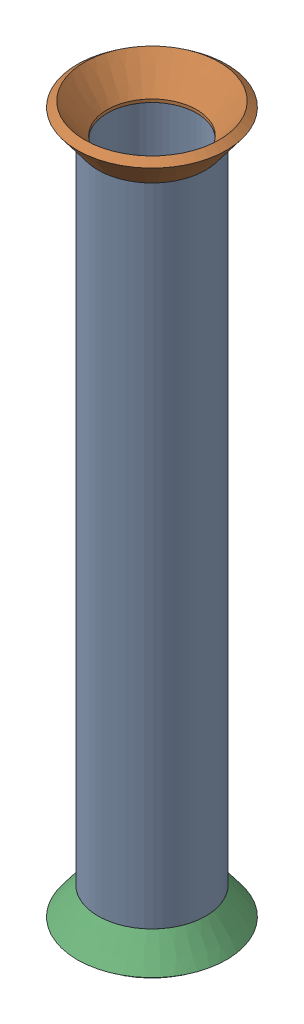
SolidWorks assembly Pipe 9, configuration Default. Lengths in mm.
Overall size (17.61 83.98 17.61).
3 component instances, 2 part files, 4 mates.
Components (placement in the parent):
- Part13-1: Part13 [Default<As Machined>] at origin size (12.7 76.2 12.7)
- Flared pipe end - .5 inch-1: Flared pipe end - .5 inch [Default<As Machined>] at (0 -198.1503 277.2944) x (0.999999 0 -0.001217) z (0 1 0) size (17.59 17.59 3.89)
- Flared pipe end - .5 inch-2: Flared pipe end - .5 inch [Default<As Machined>] at (0 -274.3503 277.2944) x (-1 0 0) z (0 -1 0) size (17.59 17.59 3.89)
Mates (geometry in assembly coordinates):
- Coincident1054: coincident: plane of Part13-1 through (0 -198.1503 277.2944) normal (0 1 0); plane of Flared pipe end - .5 inch-1 through (-0.0064 -198.1503 272.0112) normal (0 -1 0)
- Concentric661: concentric: circle of Part13-1; circle of Flared pipe end - .5 inch-1
- Coincident1624: coincident: plane of Part13-1 through (0 -274.3503 277.2944) normal (0 -1 0); plane of Flared pipe end - .5 inch-2 through (0 -274.3503 272.0112) normal (0 1 0)
- Coincident1625: coincident: circle of Part13-1; circle of Flared pipe end - .5 inch-2
